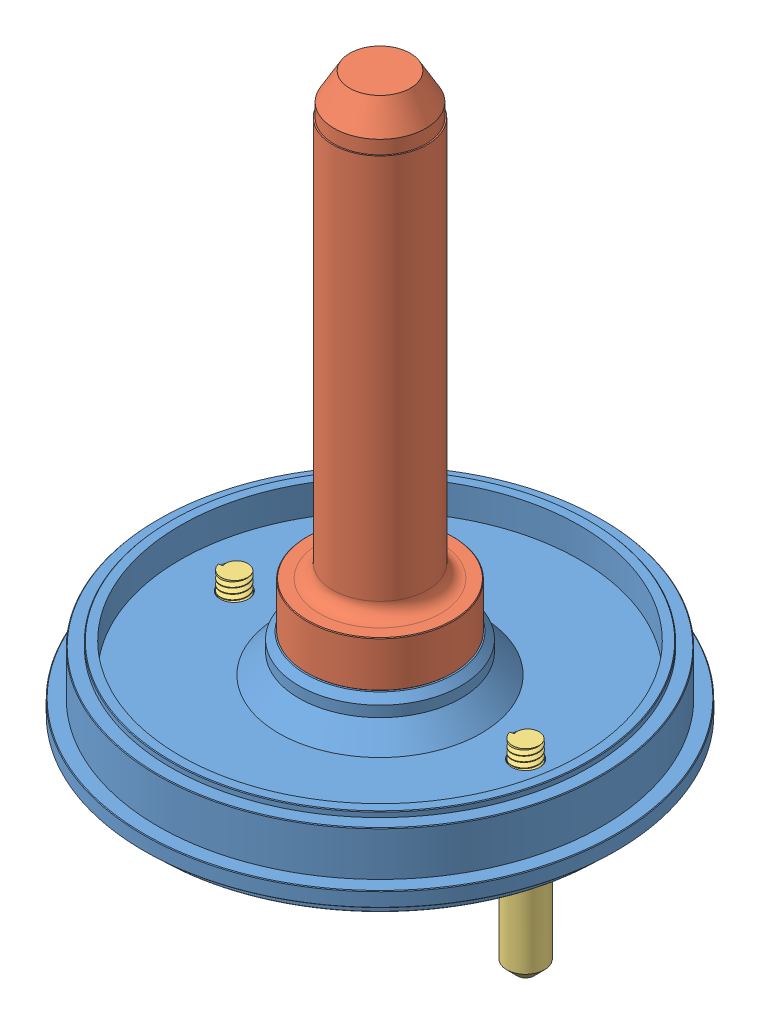
SolidWorks assembly Portal Seal Assembly, configuration Default. Lengths in mm.
Overall size (175 262.2 175).
4 component instances, 3 part files, 6 mates.
Components (placement in the parent):
- Portal Seal Installer-1: Portal Seal Installer [Default] at (-54.805 -11.1479 25.6234) size (175 32 175)
- Handle For Sealer-1: Handle For Sealer [Default] at (-54.805 200.8521 25.6234) x (0.944456 0 0.328639) z (0.328639 0 -0.944456) size (54.2 200 54.2)
- Studs-1: Studs [Default] at (-108.805 -61.3479 25.6234) x (0.971068 0 -0.238803) z (0.238803 0 0.971068) size (18 75.89 18)
- Studs-2: Studs [Default] at (-0.805 -61.3479 25.6234) x (0.97443 0 -0.22469) z (0.22469 0 0.97443) size (18 75.89 18)
Mates (geometry in assembly coordinates):
- Coincident1: coincident anti-aligned: axis of Portal Seal Installer-1 through (-54.805 15.6021 25.6234) axis (0 -1 0); axis of Handle For Sealer-1 through (-54.805 42.8521 25.6234) axis (0 1 0)
- Coincident2: coincident anti-aligned: plane of Portal Seal Installer-1 through (-38.305 20.8521 25.6234) normal (0 1 0); plane of Handle For Sealer-1 through (-38.7493 20.8521 31.2103) normal (0 -1 0)
- Coincident3: coincident anti-aligned: axis of Portal Seal Installer-1 through (-108.805 -3.0979 25.6234) axis (0 1 0); axis of Studs-1 through (-108.805 -22.3479 25.6234) axis (0 -1 0)
- Coincident4: coincident anti-aligned: axis of Portal Seal Installer-1 through (-0.805 -3.0979 25.6234) axis (0 1 0); axis of Studs-2 through (-0.805 -3.5979 25.6234) axis (0 -1 0)
- Coincident5: coincident anti-aligned: plane of Portal Seal Installer-1 through (-24.555 -3.3479 25.6234) normal (0 -1 0); plane of Studs-2 through (4.0184 -3.3479 24.5112) normal (0 1 0)
- Coincident6: coincident anti-aligned: plane of Portal Seal Installer-1 through (-24.555 -3.3479 25.6234) normal (0 -1 0); plane of Studs-1 through (-103.9982 -3.3479 24.4413) normal (0 1 0)
